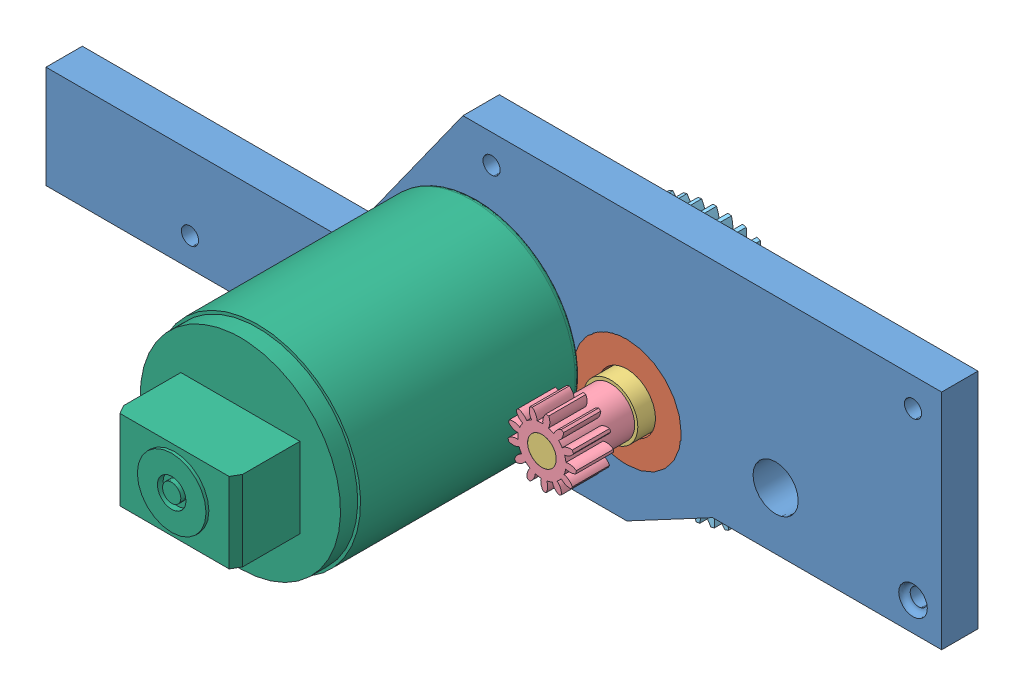
SolidWorks assembly MotorMountIzquierdoAlvaro, configuration Predeterminado. Lengths in mm.
Overall size (154.41 52.29 69.5).
9 component instances, 6 part files, 8 mates.
Components (placement in the parent):
- B_Motor_Izquierda_Alvaro-1: B_Motor_Izquierda_Alvaro [Predeterminado] at (-34.1963 -12.2627 153.2797) size (154.41 47 6.35)
- valero-1: valero [Predeterminado] at (18.135 -11.4835 154.6297) x (0.998644 0.052052 0) z (0 0 1) size (19 19 5)
- CopleEngrane-1: CopleEngrane [Predeterminado] at (-31.5769 -5.0613 154.697) x (0 0 -1) z (0.99656 0.08288 0) size (30.68 43.16 43.16)
  - Cople-1: Cople [Predeterminado] at (4.4173 -10.5202 49.0087) x (0 0 -1) z (0 -1 0) size (34.5 28.68 34.5)
  - Gear 13T-1: Gear 13T [Default] at (-13.2577 -10.5202 49.0087) x (-1 0 0) z (0 0 -1) size (12 11.88 11.96)
  - Gear_52T-1: Gear_52T [Predeterminado] at (4.4173 -10.5202 49.0087) size (6.5 43.16 43.16)
- MotorEngrane-1: MotorEngrane [Predeterminado] at (-13.0143 56.8165 177.6136) x (-1 0 0) z (0 -1 0) size (36 69.5 36)
  - Motor-1: Motor [Default] at (-5.1493 -20.5161 68.3) size (36 68.3 36)
  - Gear 13T-1: Gear 13T [Default] at (-5.1493 27.4839 68.3) x (0 1 0) z (-0.927124 0 -0.374755) size (12 11.88 11.96)
Mates (geometry in assembly coordinates):
- Concéntrica1: concentric: cylinder of B_Motor_Izquierda_Alvaro-1 through (18.135 -11.4835 154.6297) axis (0 0 1) radius 11; cylinder of valero-1 through (18.135 -11.4835 159.6297) axis (0 0 -1) radius 9.5
- Coincidente1: coincident: plane of B_Motor_Izquierda_Alvaro-1 through (18.135 -11.4835 154.6297) normal (0 0 1); plane of valero-1 through (18.135 -11.4835 154.6297) normal (0 0 -1)
- Concéntrica2: concentric: cylinder of valero-1 through (18.135 -11.4835 153.2797) axis (0 0 1) radius 5; cylinder of CopleEngrane-1/Cople-1 through (18.135 -11.4835 162.4547) axis (0 0 -1) radius 4.75
- Coincidente2: coincident: plane of B_Motor_Izquierda_Alvaro-1 through (-34.1963 -12.2627 153.2797) normal (0 0 -1); plane of CopleEngrane-1/Cople-1 through (18.135 -11.4835 153.2797) normal (0 0 1)
- Concéntrica3: concentric: cylinder of B_Motor_Izquierda_Alvaro-1 through (-7.865 -11.4835 159.6297) axis (0 0 -1) radius 7.5; cylinder of MotorEngrane-1/Motor-1 through (-7.865 -11.4835 155.6297) axis (0 0 1) radius 5.1
- Paralelo2: parallel: cylinder of B_Motor_Izquierda_Alvaro-1 through (-20.115 -8.8335 159.6297) axis (0 0 -1) radius 1.5; cylinder of MotorEngrane-1/Motor-1 through (4.4309 -13.7335 194.6297) axis (0 0 -1) radius 1.5
- Paralelo3: parallel: plane of B_Motor_Izquierda_Alvaro-1 through (73.135 17.5165 159.6297) normal (0 1 0); plane of MotorEngrane-1/Motor-1 through (18.5269 -4.4835 201.1297) normal (0 1 0)
- Coincidente4: coincident: plane of B_Motor_Izquierda_Alvaro-1 through (-34.1963 -12.2627 159.6297) normal (0 0 1); plane of MotorEngrane-1/Motor-1 through (-7.865 -11.4835 159.6297) normal (0 0 -1)
